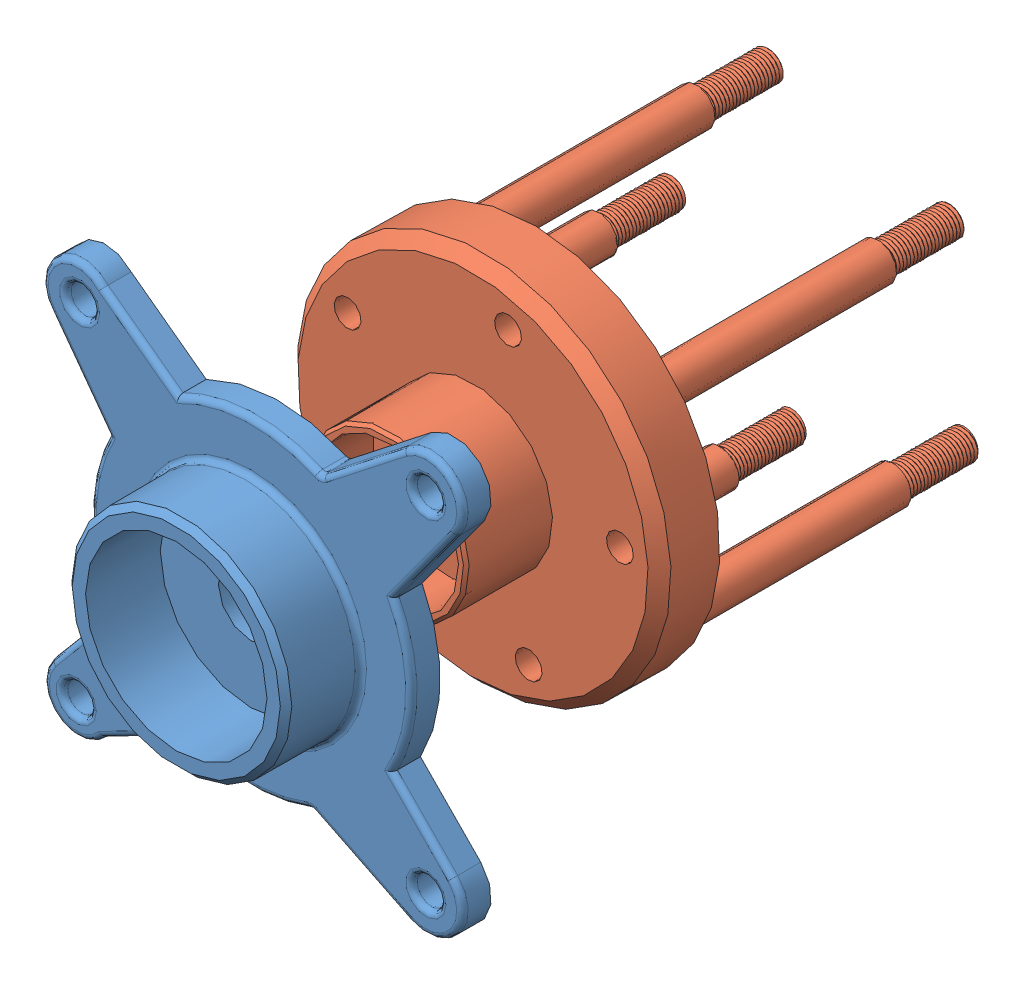
SolidWorks assembly bearingassembly, configuration Default. Lengths in mm.
Overall size (215.75 215.75 289.63).
2 component instances, 2 part files, 1 mates.
Components (placement in the parent):
- mountingbracket-01-2: mountingbracket-01 [Default] at origin size (185.79 186.24 60.96)
- hub-01-2: hub-01 [Default] at (0 0 -110.8045) x (-0.923728 -0.383049 0) z (0 0 -1) size (165.1 165.1 196.61)
Mates (geometry in assembly coordinates):
- Concentric2: concentric anti-aligned: circle of mountingbracket-01-2; circle of hub-01-2
